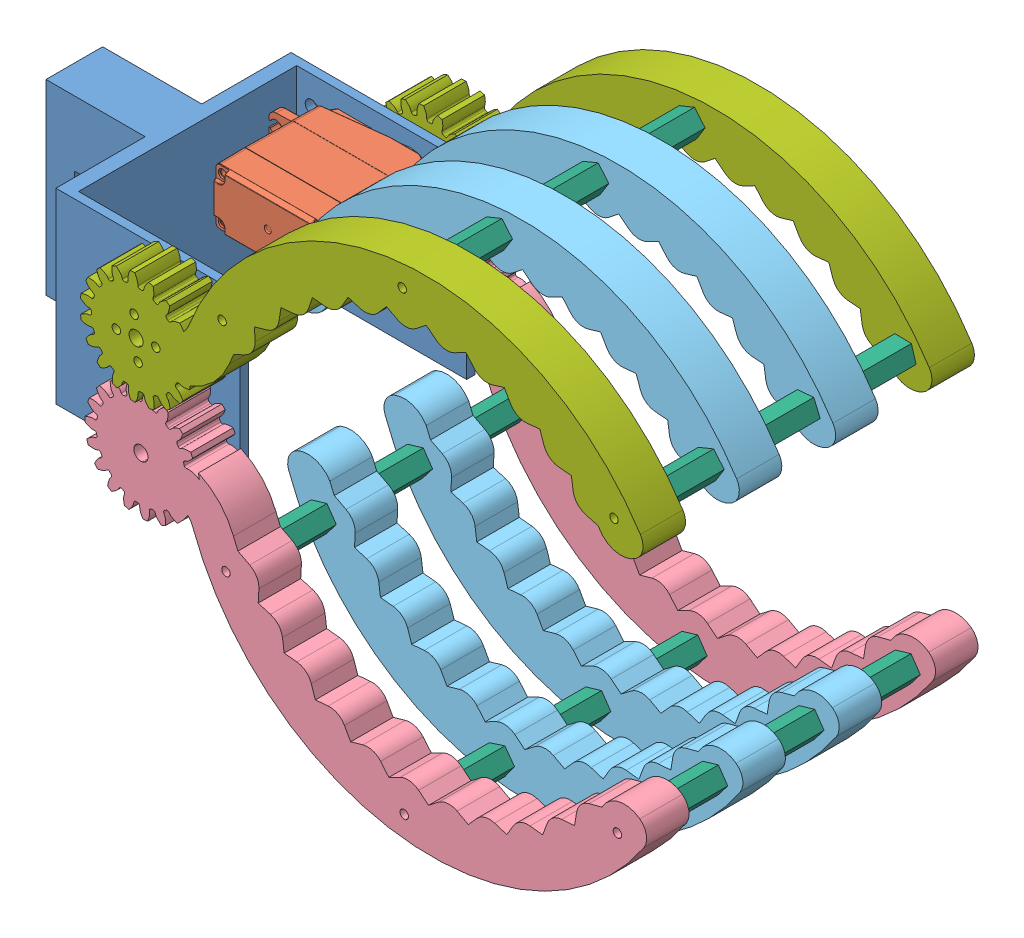
SolidWorks assembly 装配体_爪子加舵机, configuration Default. Lengths in mm.
Overall size (261.78 194.91 118.7).
31 component instances, 7 part files, 9 mates.
Components (placement in the parent):
- 3.固定舵机盘-1: 3.固定舵机盘 [默认] at origin size (100 66 87)
- 4.35KGservo-1: 4.35KGservo [默认] at (35.5165 11.5325 23.201) x (1 0 0) z (0 1 0) size (62.21 45.03 20.04)
- 5.舵机圆形头-1: 5.舵机圆形头 [默认] at (35.5165 11.5325 23.6787) x (1 0 0) z (0 1 0) size (19.5 4.4 19.5)
- 装配体_右爪子-1: 装配体_右爪子 [Default] at (137.7363 -24.1002 -6.499) x (0.117021 0.993129 0) z (0 0 -1) size (79.93 200.48 117)
  - 1_2.右爪子表面_打印两个-1: 1_2.右爪子表面_打印两个 [Varsayılan] at origin size (79.93 200.48 15)
  - 1_3.爪子中间_打印四个-1: 1_3.爪子中间_打印四个 [Varsayılan] at (-2.9763 8.2953 -34) size (58.35 161.77 15)
  - 2.铜柱连接件-1: 2.铜柱连接件 [Varsayılan] at (-63.7872 8.2778 -21.5) size (9.37 9.17 19)
  - 2.铜柱连接件-2: 2.铜柱连接件 [Varsayılan] at (-23.2882 79.2861 -21.5) size (9.37 9.17 19)
  - 2.铜柱连接件-3: 2.铜柱连接件 [Varsayılan] at (-23.2882 79.2861 -55.5) size (9.37 9.17 19)
  - 2.铜柱连接件-4: 2.铜柱连接件 [Varsayılan] at (-28.7173 -59.225 -21.5) size (9.37 9.17 19)
  - 2.铜柱连接件-5: 2.铜柱连接件 [Varsayılan] at (-28.7173 -59.225 -55.5) size (9.37 9.17 19)
  - 2.铜柱连接件-6: 2.铜柱连接件 [Varsayılan] at (-23.2882 79.2861 -89.5) size (9.37 9.17 19)
  - 2.铜柱连接件-7: 2.铜柱连接件 [Varsayılan] at (-28.7173 -59.225 -89.5) size (9.37 9.17 19)
  - 2.铜柱连接件-8: 2.铜柱连接件 [Varsayılan] at (-63.7872 8.2778 -55.5) size (9.37 9.17 19)
  - 2.铜柱连接件-9: 2.铜柱连接件 [Varsayılan] at (-63.7872 8.2778 -70.5) x (-0.498458 -0.866914 0) z (0 0 -1) size (9.37 9.17 19)
  - 1_3.爪子中间_打印四个-2: 1_3.爪子中间_打印四个 [Varsayılan] at (-2.9763 8.2953 -68) size (58.35 161.77 15)
  - 1_2.右爪子表面_打印两个-2: 1_2.右爪子表面_打印两个 [Varsayılan] at (0 0 -102) size (79.93 200.48 15)
- 装配体_左爪子-1: 装配体_左爪子 [Default] at (137.8802 9.6724 87.201) x (0.101561 -0.994829 0) z (0 0 1) size (79.66 200.49 117)
  - 1_1.左爪子表面_打印两个-1: 1_1.左爪子表面_打印两个 [Varsayılan] at origin size (79.66 200.49 15)
  - 1_3.爪子中间_打印四个-1: 1_3.爪子中间_打印四个 [Varsayılan] at (-2.9202 8.1355 -34) size (58.35 161.77 15)
  - 2.铜柱连接件-1: 2.铜柱连接件 [Varsayılan] at (-28.6612 -59.3847 -21.5) x (0.366858 -0.930277 0) z (0 0 1) size (9.37 9.17 19)
  - 2.铜柱连接件-2: 2.铜柱连接件 [Varsayılan] at (-63.7311 8.1181 -21.5) x (0.366858 -0.930277 0) z (0 0 1) size (9.37 9.17 19)
  - 2.铜柱连接件-3: 2.铜柱连接件 [Varsayılan] at (-23.232 79.1263 -21.5) x (0.366858 -0.930277 0) z (0 0 1) size (9.37 9.17 19)
  - 2.铜柱连接件-4: 2.铜柱连接件 [Varsayılan] at (-23.232 79.1263 -55.5) x (-0.923835 -0.38279 0) z (0 0 1) size (9.37 9.17 19)
  - 2.铜柱连接件-5: 2.铜柱连接件 [Varsayılan] at (-63.7311 8.1181 -55.5) x (0.366858 -0.930277 0) z (0 0 1) size (9.37 9.17 19)
  - 2.铜柱连接件-6: 2.铜柱连接件 [Varsayılan] at (-28.6612 -59.3847 -55.5) x (0.366858 -0.930277 0) z (0 0 1) size (9.37 9.17 19)
  - 2.铜柱连接件-7: 2.铜柱连接件 [Varsayılan] at (-28.6612 -59.3847 -89.5) x (0.366858 -0.930277 0) z (0 0 1) size (9.37 9.17 19)
  - 2.铜柱连接件-8: 2.铜柱连接件 [Varsayılan] at (-23.232 79.1263 -89.5) x (-0.960896 -0.276909 0) z (0 0 1) size (9.37 9.17 19)
  - 2.铜柱连接件-9: 2.铜柱连接件 [Varsayılan] at (-63.7311 8.1181 -89.5) x (0.366858 -0.930277 0) z (0 0 1) size (9.37 9.17 19)
  - 1_3.爪子中间_打印四个-2: 1_3.爪子中间_打印四个 [Varsayılan] at (-2.9202 8.1355 -68) size (58.35 161.77 15)
  - 1_1.左爪子表面_打印两个-2: 1_1.左爪子表面_打印两个 [Varsayılan] at (0 0 -102) size (79.66 200.49 15)
Mates (geometry in assembly coordinates):
- 重合1: coincident anti-aligned: plane of 4.35KGservo-1 through (35.5165 11.5325 1.701) normal (0 0 -1); plane of 5.舵机圆形头-1 through (45.5165 11.5325 1.701) normal (0 0 1)
- 同心1: concentric anti-aligned: circle of 4.35KGservo-1; circle of 5.舵机圆形头-1
- 重合4: coincident anti-aligned: plane of 3.固定舵机盘-1 through (5.5165 26.5325 3.001) normal (0 0 1); plane of 4.35KGservo-1 through (35.5165 11.5325 3.001) normal (0 0 -1)
- 同心2: concentric aligned: circle of 3.固定舵机盘-1; circle of 5.舵机圆形头-1
- 重合6: coincident anti-aligned: plane of 5.舵机圆形头-1 through (45.5165 11.5325 -2.299) normal (0 0 -1); plane of 装配体_左爪子-1/1_1.左爪子表面_打印两个-2 through (205.7758 42.7721 -2.299) normal (0 0 1)
- 重合10: coincident anti-aligned: plane of 3.固定舵机盘-1 through (45.5165 -24.4675 -3.999) normal (0 0 -1); plane of 装配体_右爪子-1/1_2.右爪子表面_打印两个-1 through (205.2609 -58.3263 -3.999) normal (0 0 1)
- 同心3: concentric aligned: cylinder of 3.固定舵机盘-1 through (45.5165 -24.4675 -96.999) axis (0 0 1) radius 1.5; cylinder of 装配体_右爪子-1/1_2.右爪子表面_打印两个-1 through (45.5165 -24.4675 -18.999) axis (0 0 1) radius 2.505
- 齿轮配合1: gear = 5.001 : 5.01 mm: circle of 装配体_右爪子-1/1_2.右爪子表面_打印两个-1; circle of 装配体_左爪子-1/1_1.左爪子表面_打印两个-2
- 同心4: concentric aligned: circle of 5.舵机圆形头-1; cylinder of 装配体_左爪子-1/1_1.左爪子表面_打印两个-2 through (45.5165 11.5325 -2.299) axis (0 0 -1) radius 2.5005
